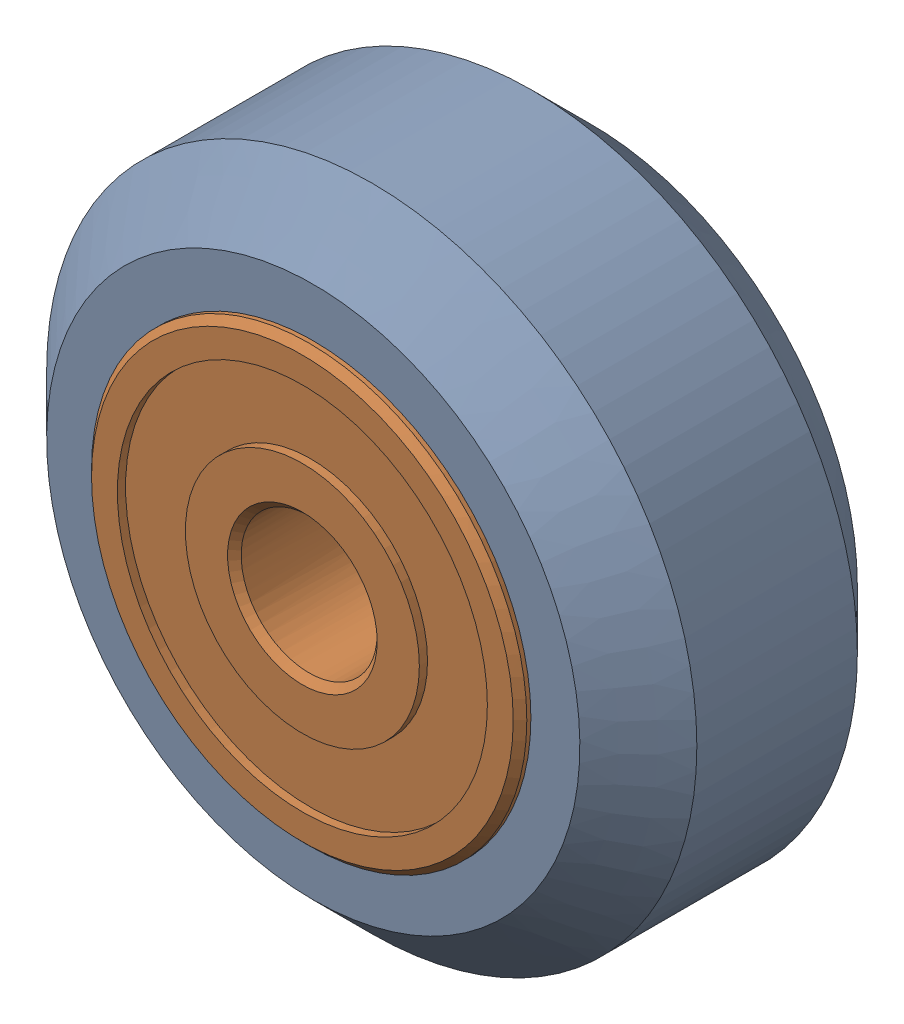
SolidWorks assembly Xtreme Solid V Wheel Assembly_6, configuration Default. Lengths in mm.
Overall size (23.9 23.9 11).
3 component instances, 2 part files, 0 mates.
Components (placement in the parent):
- Xtreme Solid V Wheel-1: Xtreme Solid V Wheel [Default] at (-115.15 -55.79 30) x (0 0 1) z (-1 0 0) size (10.2 23.9 23.9)
- Wheel+Kit+-+5x16x5mm+Sealed+Radial+Ball+Bearing.step.f3d-1: Wheel+Kit+-+5x16x5mm+Sealed+Radial+Ball+Bearing.step.f3d [Default] at (-115.15 -55.79 30) x (0 1 0) z (-1 0 0) size (16 5 16)
- Wheel+Kit+-+5x16x5mm+Sealed+Radial+Ball+Bearing.step.f3d-2: Wheel+Kit+-+5x16x5mm+Sealed+Radial+Ball+Bearing.step.f3d [Default] at (-115.15 -55.79 30) x (0 1 0) z (1 0 0) size (16 5 16)
